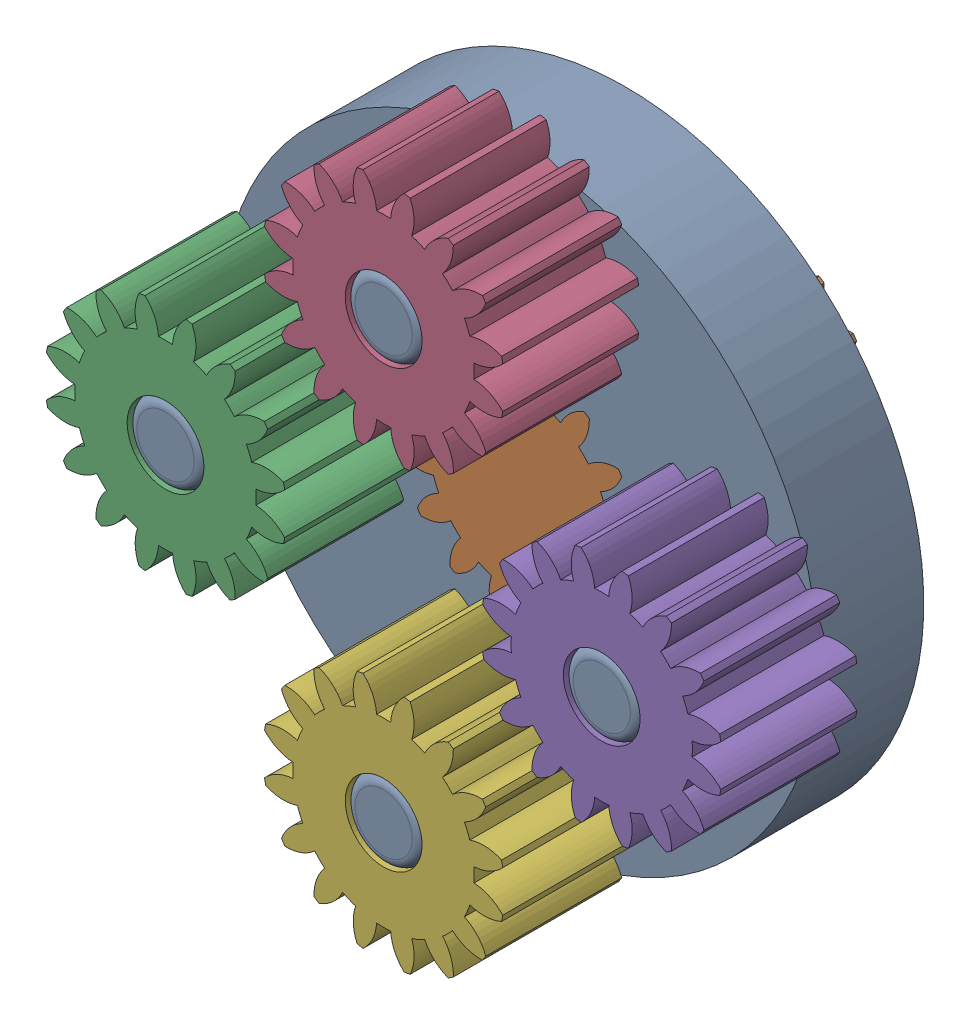
SolidWorks assembly am-XXXX - 4_1 Stage, configuration Default. Lengths in mm.
Overall size (38.96 38.96 19.84).
6 component instances, 3 part files, 0 mates.
Components (placement in the parent):
- am-XXXX - 57 Sport Stage Carrier Plate-1: am-XXXX - 57 Sport Stage Carrier Plate [Default] at origin size (31.12 31.12 12.6)
- 16T Sun Gear-1: 16T Sun Gear [Default] at (2.1233 -0.5181 -1.3921) x (0 0 -1) z (-1 0 0) size (12.75 12.42 12.42)
- 16T Planet Gear-1: 16T Planet Gear [Default] at (-11.2886 -1.3776 8.289) x (0 0 1) z (0.923728 0.383049 0) size (7.09 12.42 12.42)
- 16T Planet Gear-2: 16T Planet Gear [Default] at (-1.3776 11.2886 8.289) x (0 0 1) z (0.383049 -0.923728 0) size (7.09 12.42 12.42)
- 16T Planet Gear-3: 16T Planet Gear [Default] at (11.2886 1.3776 8.289) x (0 0 1) z (-0.923728 -0.383049 0) size (7.09 12.42 12.42)
- 16T Planet Gear-4: 16T Planet Gear [Default] at (1.3776 -11.2886 8.289) x (0 0 1) z (-0.383049 0.923728 0) size (7.09 12.42 12.42)
